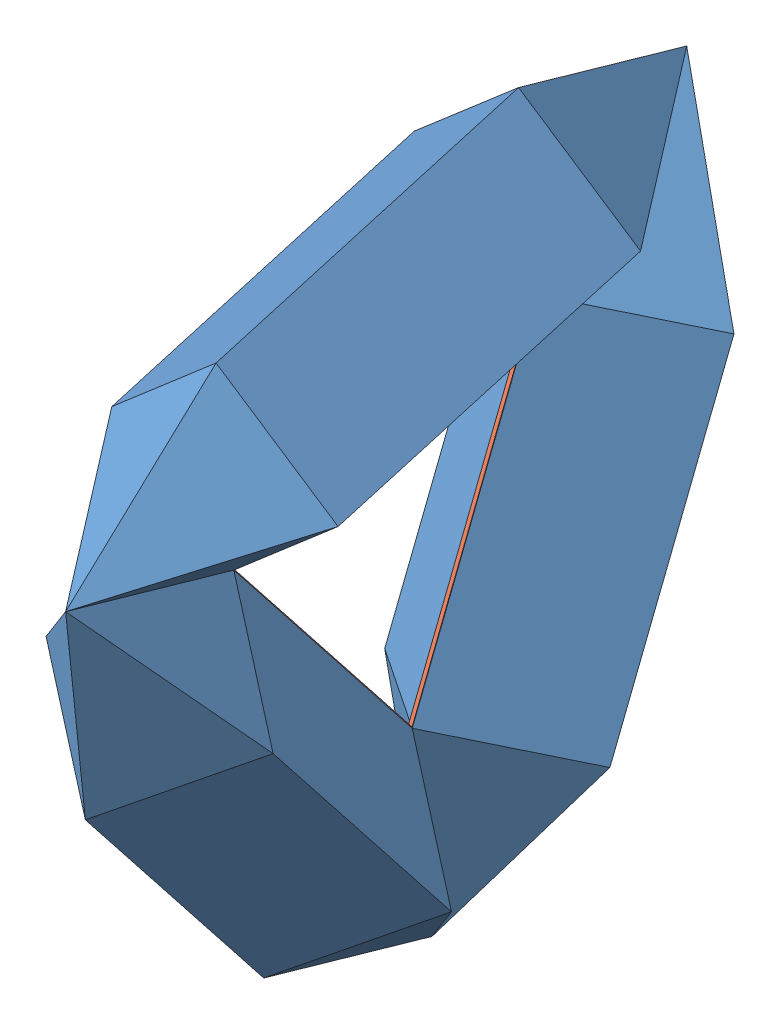
SolidWorks assembly Assemblage1IGS, configuration Défaut. Lengths in mm.
Overall size (818.36 2414.41 2533.71).
4 component instances, 2 part files, 0 mates.
Components (placement in the parent):
- Ballon_2-1: Ballon_2 [Défaut] at (111.468 3273.9333 356.2159) x (-0.091454 0.165626 -0.981939) z (-0.650374 0.73678 0.184848) size (2053.61 430.1 430.1)
- Ballon_2-2: Ballon_2 [Défaut] at (-212.8655 2991.9886 338.8669) x (-0.104181 -0.770079 -0.629384) z (-0.666053 -0.415938 0.619168) size (2053.61 430.1 430.1)
- Ballon_2-3: Ballon_2 [Défaut] at (-651.9731 2130.7718 -544.4942) x (0.012727 0.935705 -0.352555) z (0.627246 -0.282056 -0.725953) size (2053.61 430.1 430.1)
- supportTEMP_2-1: supportTEMP_2 [Défaut] at (-268.5279 3075.3181 -151.0901) x (0.091454 -0.165626 0.981939) z (0.993519 -0.051661 -0.101247) size (1000 866.03 10)
